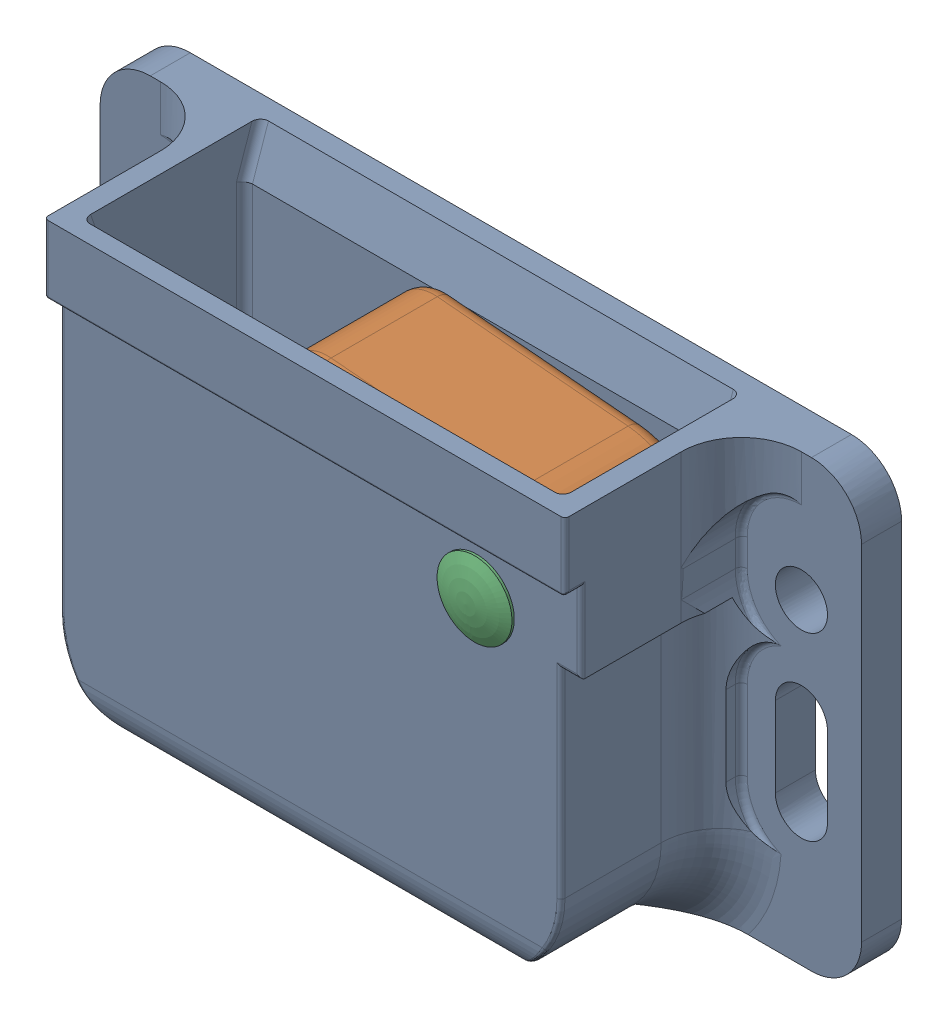
SolidWorks assembly SW3dPS-C3-810_C3_Grabber_Door_Catch_clf, configuration Default. Lengths in mm.
Overall size (48.27 28.42 13.73).
3 component instances, 3 part files, 0 mates.
Components (placement in the parent):
- SW3dPS-C3-810_c3_housing_clf-1: SW3dPS-C3-810_c3_housing_clf [Default] at origin size (48.27 28.42 13.73)
- SW3dPS-C3-810_C3_Pawl_Clf-1: SW3dPS-C3-810_C3_Pawl_Clf [Default] at (-1.6193 3.0428 -9.271) x (0.996195 -0.087156 0) z (0 0 1) size (18.2 16.64 9.27)
- SW3dPS-C3-810_c3_rivet_clf-1: SW3dPS-C3-810_c3_rivet_clf [Default] at origin size (4.75 4.75 12.92)
